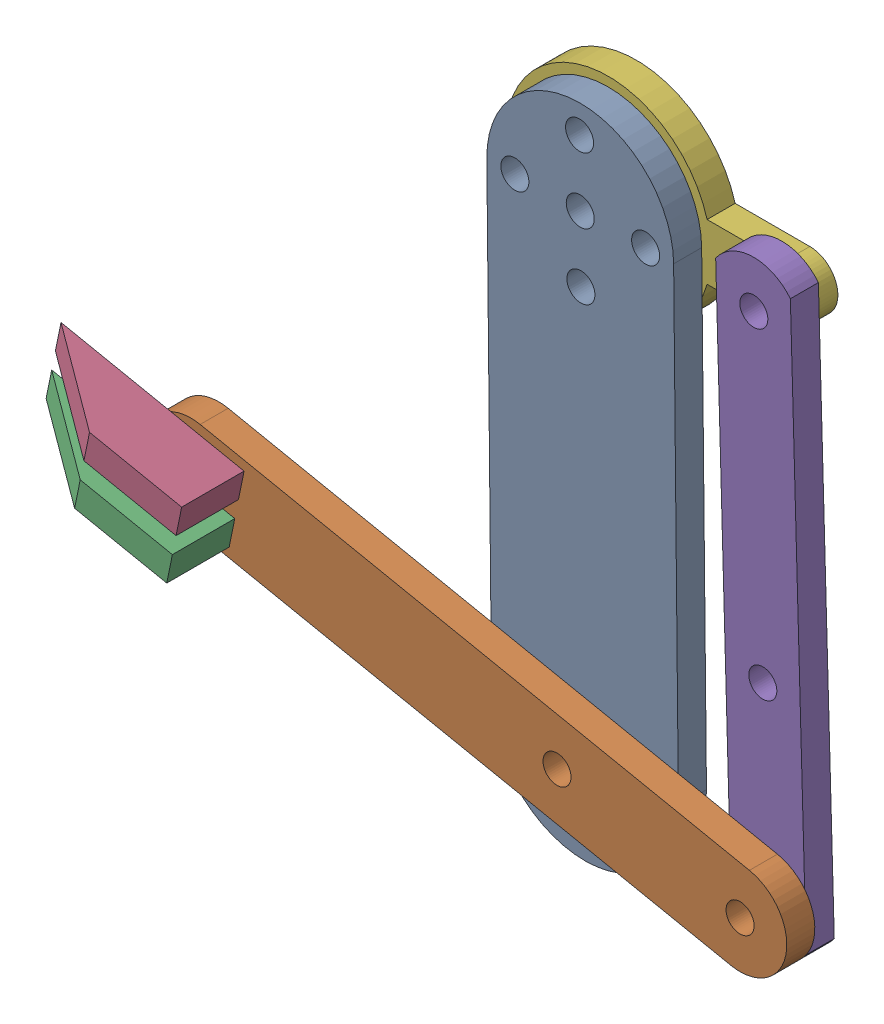
SolidWorks assembly Assem2, configuration Default. Lengths in mm.
Overall size (80.19 71.1 15.68).
6 component instances, 5 part files, 12 mates.
Components (placement in the parent):
- d1-2: d1 [Default] at (-22.5381 53.9588 82.2172) x (-0.010259 0.999947 0) z (0.999947 0.010259 0) size (70 3 20)
- d2-1: d2 [Default] at (-72.2194 6.9209 88.2172) x (-0.97999 0.199048 0) z (-0.199048 -0.97999 0) size (70 3 10)
- claw-1: claw [Default] at (-66.5233 9.8456 85.2172) x (0.97999 -0.199048 0) z (0 0 -1) size (20 3 9.68)
- claw-2: claw [Default] at (-65.5281 14.7455 85.2172) x (0.97999 -0.199048 0) z (0 0 -1) size (20 3 9.68)
- hand2-1: hand2 [Default] at (-10.0411 56.9684 82.2172) x (-0.028329 0.999599 0) z (0.999599 0.028329 0) size (64 3 8)
- hand3-1: hand3 [Default] at (-32.5376 53.8563 79.2172) x (0 -1 0) z (-1 0 0) size (22 3 32.58)
Mates (geometry in assembly coordinates):
- Coincident1: coincident anti-aligned: circle of d1-2; circle of d2-1
- Coincident2: coincident: line of d2-1 through (-67.1204 6.9056 85.2172) axis (-0.97999 0.199048 0); plane of claw-1 through (-67.1204 6.9056 85.2172) normal (0 0 -1)
- Coincident3: coincident anti-aligned: line of d2-1 through (-66.5233 9.8456 85.2172) axis (-0.199048 -0.97999 0); line of claw-1 through (-67.1204 6.9056 85.2172) axis (0.199048 0.97999 0)
- Coincident4: coincident anti-aligned: line of d2-1 through (-71.4232 10.8408 85.2172) axis (0.97999 -0.199048 0); line of claw-1 through (-66.5233 9.8456 85.2172) axis (-0.97999 0.199048 0)
- Coincident6: coincident aligned: line of d2-1 through (-66.1252 11.8056 85.2172) axis (-0.97999 0.199048 0); line of claw-2 through (-66.1252 11.8056 85.2172) axis (-0.97999 0.199048 0)
- Coincident7: coincident aligned: line of d2-1 through (-71.0251 12.8008 85.2172) axis (0.199048 0.97999 0); line of claw-2 through (-71.0251 12.8008 85.2172) axis (0.199048 0.97999 0)
- Coincident8: coincident anti-aligned: circle of d2-1; circle of hand2-1
- Coincident9: coincident anti-aligned: plane of d2-1 through (-71.2242 11.8208 85.2172) normal (0 0 -1); plane of hand2-1 through (-13.9545 53.8563 85.2172) normal (0 0 1)
- Concentric1: concentric aligned: circle of d1-2; circle of hand3-1
- Coincident10: coincident anti-aligned: plane of d1-2 through (-32.5376 53.8563 82.2172) normal (0 0 -1); plane of hand3-1 through (-32.5376 53.8563 82.2172) normal (0 0 1)
- Coincident11: coincident aligned: circle of hand2-1; circle of hand3-1
- Coincident12: coincident anti-aligned: plane of hand2-1 through (-13.9545 53.8563 82.2172) normal (0 0 -1); plane of hand3-1 through (-32.5376 53.8563 82.2172) normal (0 0 1)
